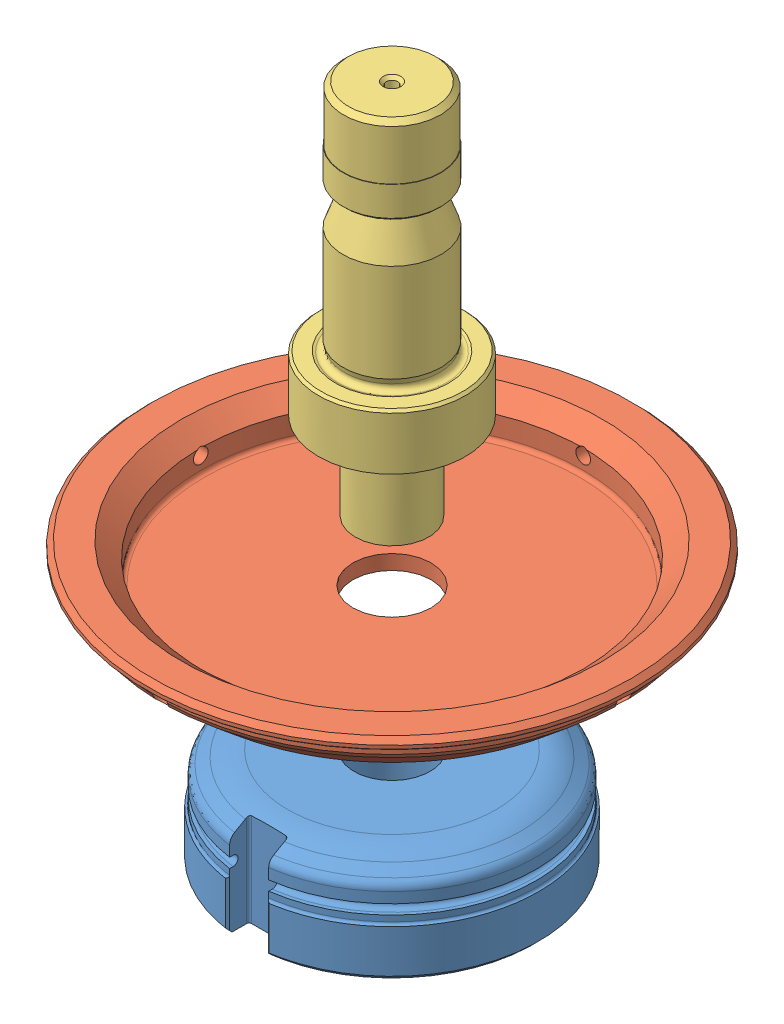
SolidWorks assembly ASSEMBLY, configuration Valor predeterminado. Lengths in mm.
Overall size (100 138.37 100).
3 component instances, 3 part files, 6 mates.
Components (placement in the parent):
- DIE-1: DIE [ MATTRRE34000000000000000300001] at origin size (60 20 59.71)
- EXTRACTOR-1: EXTRACTOR [Default] at (0 46.0783 0) size (100 11 100)
- PUNCH-1: PUNCH [Valor predeterminado] at (0 61.3663 0) x (-0.924634 0 -0.380856) z (0.380856 0 -0.924634) size (30 77 30)
Mates (geometry in assembly coordinates):
- Coincidente1: coincident aligned: plane of DIE-1 through (0 0 0) normal (0 0 1)
- Coincidente2: coincident aligned: plane of DIE-1 through (0 0 0) normal (0 1 0)
- Coincidente3: coincident aligned: plane of DIE-1 through (0 0 0) normal (1 0 0)
- Concêntrico1: concentric aligned: cylinder of DIE-1 through (0 17 0) axis (0 1 0) radius 7.8; cylinder of EXTRACTOR-1 through (0 46.0783 0) axis (0 1 0) radius 8
- Coincidente4: coincident aligned: plane of DIE-1 through (0 0 0) normal (1 0 0); plane of EXTRACTOR-1 through (0 46.0783 0) normal (1 0 0)
- Concêntrico2: concentric anti-aligned: cylinder of DIE-1 through (0 17 0) axis (0 1 0) radius 7.8; cylinder of PUNCH-1 through (0 79.3663 0) axis (0 -1 0) radius 7.5
